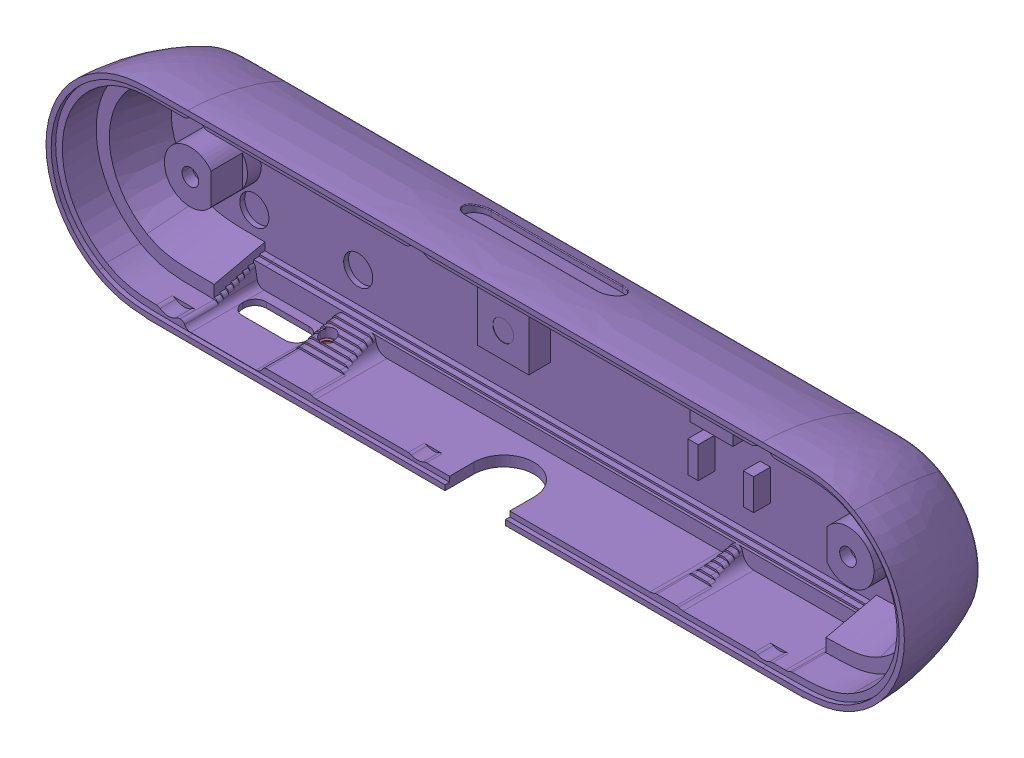
SolidWorks assembly AM0600133_ASM_2_ASM, configuration AM0600133_ASM_2_ASM. Lengths in mm.
Overall size (124.01 29.03 14.45).
14 component instances, 4 part files, 0 mates.
Components (placement in the parent):
- FAS000227_ASM_2_ASM-1: FAS000227_ASM_2_ASM [FAS000227_ASM_2_ASM] at (-47.5 0 -25.4937) x (-1 0 0) z (0 1 0) size (5.62 3.92 5.68)
  - 91732A649_ASM_1_ASM-1: 91732A649_ASM_1_ASM [91732A649_ASM_1_ASM] at origin size (5.62 3.92 5.68)
    - SWEEP1_1-1: SWEEP1_1 [SWEEP1_1] at origin size (5.62 3.92 5.68)
- FAS000227_ASM_2_ASM-2: FAS000227_ASM_2_ASM [FAS000227_ASM_2_ASM] at (47.5 0 -25.4937) x (-1 0 0) z (0 1 0) size (5.62 3.92 5.68)
  - 91732A649_ASM_1_ASM-1: 91732A649_ASM_1_ASM [91732A649_ASM_1_ASM] at origin size (5.62 3.92 5.68)
    - SWEEP1_1-1: SWEEP1_1 [SWEEP1_1] at origin size (5.62 3.92 5.68)
- FAS000226_ASM_2_ASM-1: FAS000226_ASM_2_ASM [FAS000226_ASM_2_ASM] at (-44.51 -14.325 -19.85) size (2.7 1.95 2.7)
  - 91732A181_ASM_1_ASM-1: 91732A181_ASM_1_ASM [91732A181_ASM_1_ASM] at origin size (2.7 1.95 2.7)
    - SWEEP1_1_2_3_1-1: SWEEP1_1_2_3_1 [SWEEP1_1_2_3_1] at origin size (2.7 1.95 2.7)
- FAS000226_ASM_2_ASM-2: FAS000226_ASM_2_ASM [FAS000226_ASM_2_ASM] at (-29.51 -14.325 -19.85) size (2.7 1.95 2.7)
  - 91732A181_ASM_1_ASM-1: 91732A181_ASM_1_ASM [91732A181_ASM_1_ASM] at origin size (2.7 1.95 2.7)
    - SWEEP1_1_2_3_1-1: SWEEP1_1_2_3_1 [SWEEP1_1_2_3_1] at origin size (2.7 1.95 2.7)
- MEC060316_8-1: MEC060316_8 [MEC060316_8] at origin size (124.01 29.03 14.45)
- MEC060019_1-1: MEC060019_1 [MEC060019_1] at (-2.4 9.5 -21.62) x (-1 0 0) z (0 1 0) size (1.6 1.6 1.6)
